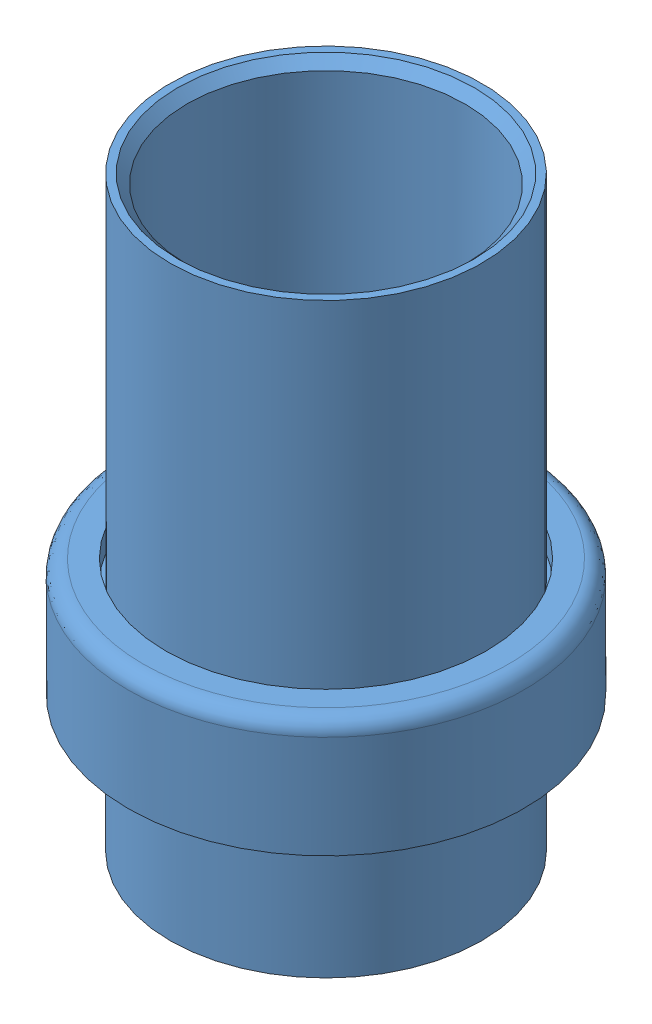
SolidWorks assembly Assem1, configuration Default. Lengths in mm.
Overall size (158 234.25 158).
2 component instances, 2 part files, 3 mates.
Components (placement in the parent):
- Fluidizer Union-1: Fluidizer Union [Default] at origin size (158 234.25 158)
- Fluidizer-1: Fluidizer [Default] at (0 -0.8 1.2765) x (-1 0 0) z (0 0 -1) size (136 75 136)
Mates (geometry in assembly coordinates):
- Concentric5: concentric anti-aligned: cylinder of Fluidizer Union-1 through (0 -82.75 41.2765) axis (0 -1 0) radius 1.3526; cylinder of Fluidizer-1 through (0 -13.5 41.2765) axis (0 1 0) radius 1.8986
- Coincident2: coincident anti-aligned: plane of Fluidizer-1 through (0 -0.8 1.2765) normal (-1 0 0); plane of assembly
- Coincident3: coincident anti-aligned: plane of Fluidizer Union-1 through (35 -75 0) normal (0 1 0); plane of Fluidizer-1 through (0 -75 1.2765) normal (0 -1 0)
